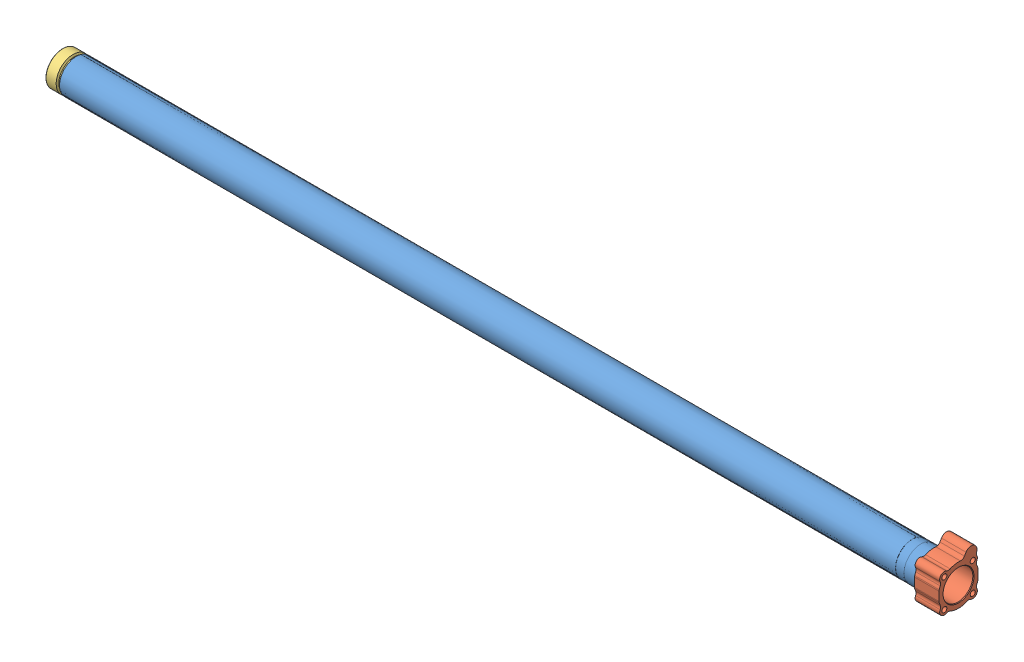
SolidWorks assembly 6344565, configuration Default. Lengths in mm.
Overall size (2122 113.03 92).
3 component instances, 3 part files, 9 mates.
Components (placement in the parent):
- 6344566-1: 6344566 [Default] at (-2087 0 0) x (-1 0 0) z (0 0 -1) size (2031 80 80)
- 6344547-1: 6344547 [Default] at (1 0 0) x (0 0 1) z (-1 0 0) size (92 113.03 58)
- 6238544-1: 6238544 [Default] at (-2085 0 0) x (-1 0 0) z (0 0 -1) size (37 80 80)
Mates (geometry in assembly coordinates):
- Coincident11: coincident aligned: plane of 6344547-1 through (0 90 0) normal (1 0 0); plane of assembly through (0 0 0) normal (1 0 0)
- Concentric4: concentric aligned: cylinder of 6344566-1 through (-1964.2158 0 0) axis (1 0 0) radius 40; cylinder of 6344547-1 through (-59 0 0) axis (1 0 0) radius 47.5
- Concentric5: concentric: cylinder of 6344547-1 through (-59 0 0) axis (1 0 0) radius 47.5
- Coincident12: coincident anti-aligned: plane of 6344566-1 through (-56 37.5 0) normal (1 0 0); plane of 6344547-1 through (-56 37.5 0) normal (-1 0 0)
- Parallel6: parallel aligned: plane of 6344547-1 through (1 0 0) normal (0 0 1); plane of assembly through (0 0 0) normal (0 0 1)
- Parallel7: parallel anti-aligned: plane of 6344566-1 through (-2087 0 0) normal (0 0 -1); plane of assembly through (0 0 0) normal (0 0 1)
- Concentric6: concentric aligned: cylinder of 6344566-1 through (-1964.2158 0 0) axis (1 0 0) radius 35; cylinder of 6238544-1 through (-2053.7231 0 0) axis (1 0 0) radius 36
- Coincident16: coincident anti-aligned: plane of 6344566-1 through (-2087 35 0) normal (-1 0 0); plane of 6238544-1 through (-2087 36 0) normal (1 0 0)
- Coincident17: coincident anti-aligned: plane of 6238544-1 through (-2085 0 0) normal (0 0 -1); plane of assembly through (0 0 0) normal (0 0 1)
